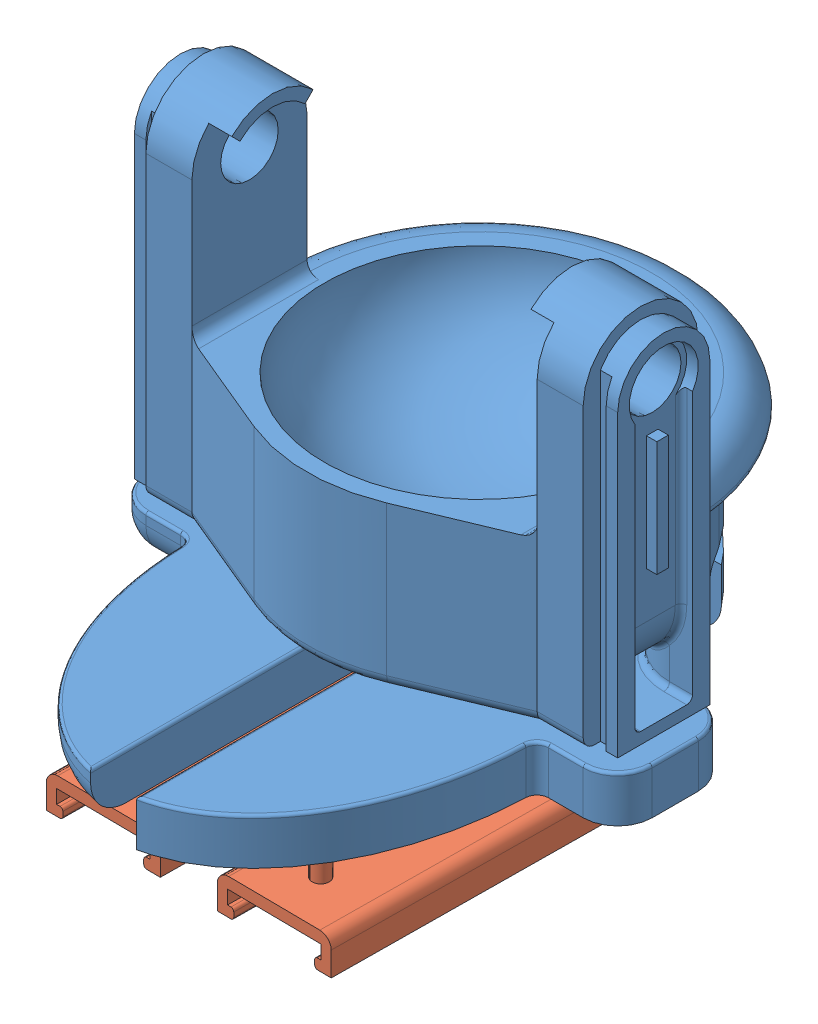
SolidWorks assembly foodwell-with endcaps, configuration Default. Lengths in mm.
Overall size (44 44.1 51.61).
3 component instances, 2 part files, 4 mates.
Components (placement in the parent):
- foodwell_all-1: foodwell_all [Default] at origin size (44 36.18 51.61)
- foodwell_endcap-1: foodwell_endcap [Default] at (-2.9921 -10 24.7562) x (-0.999952 0 -0.009754) z (0 -1 0) size (10 31 8.1)
- foodwell_endcap-2: foodwell_endcap [Default] at (12.0072 -10 24.9025) x (-0.999952 0 -0.009754) z (0 -1 0) size (10 31 8.1)
Mates (geometry in assembly coordinates):
- Coincident3: coincident aligned: plane of foodwell_endcap-1 through (-2.9921 -11 24.7562) normal (-0.009754 0 0.999952); plane of foodwell_endcap-2 through (12.0072 -11 24.9025) normal (-0.009754 0 0.999952)
- Coincident4: coincident aligned: plane of foodwell_endcap-1 through (-2.7385 -10 -1.2426) normal (0 1 0); plane of foodwell_endcap-2 through (12.2608 -10 -1.0963) normal (0 1 0)
- Distance3: distance = 5 mm anti-aligned: plane of foodwell_endcap-2 through (2.0076 -11 24.8049) normal (-0.999952 0 -0.009754); plane of foodwell_endcap-1 through (-2.9921 -11 24.7562) normal (0.999952 0 0.009754)
- Coincident9: coincident anti-aligned: plane of foodwell_all-1 through (0 -5 0) normal (0 -1 0); plane of foodwell_endcap-2 through (7.0464 -5 20.8539) normal (0 1 0)
